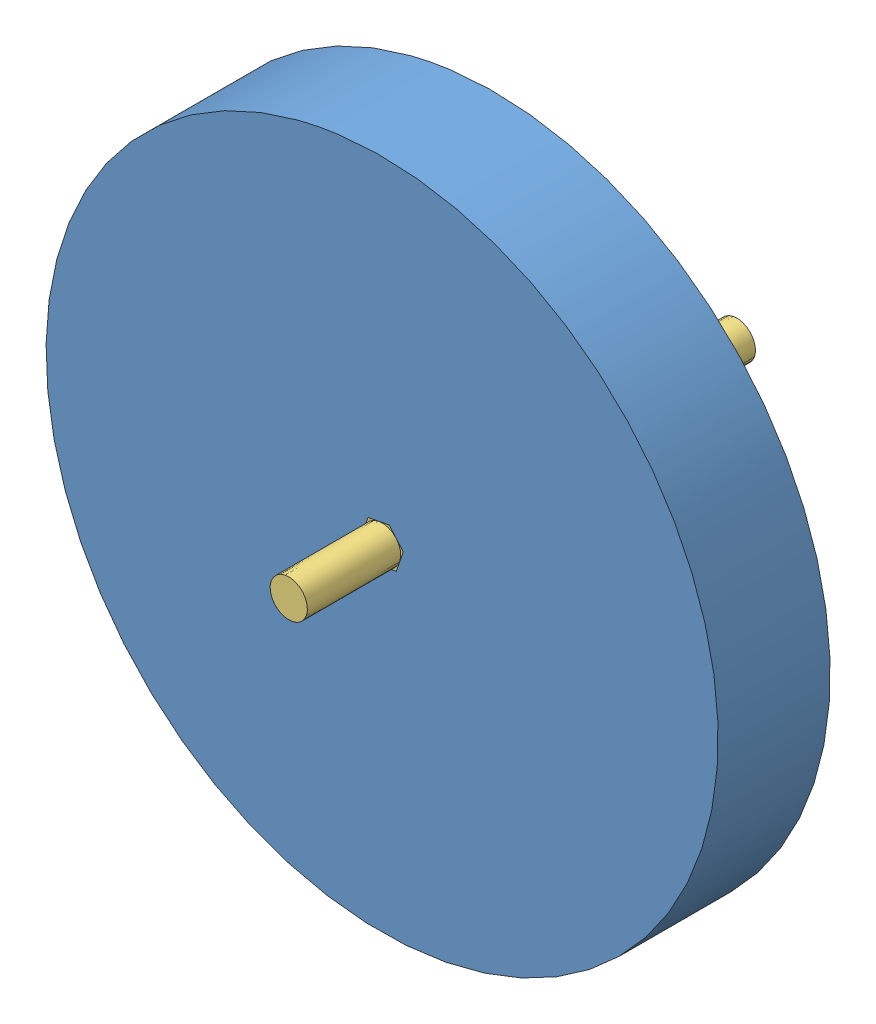
SolidWorks assembly Drivetrain wheel axle and belt gear free, configuration Default. Lengths in mm.
Overall size (133.9 133.9 76.2).
3 component instances, 3 part files, 9 mates.
Components (placement in the parent):
- Wheel-1: Wheel [Default] at (0 57.15 19.05) x (-0.189612 0.981859 0) z (0 0 -1) size (114.3 114.3 19.05)
- belt gear-2: belt gear [Default] at (0 57.15 -12.7) x (-0.945121 0.326721 0) z (0 0 1) size (39.94 39.94 6.35)
- wheel axle free-1: wheel axle free [Default] at (0 57.15 34.925) x (-0.755509 -0.655138 0) z (0 0 -1) size (6.35 7.33 76.2)
Mates (geometry in assembly coordinates):
- Coincident3: coincident: circle of Wheel-1; point of assembly
- Tangent1: tangent: cylinder of Wheel-1 through (0 57.15 0) axis (0 0 1) radius 57.15; plane of assembly through (0 0 0) normal (0 1 0)
- Parallel1: parallel: plane of Wheel-1 through (0 57.15 19.05) normal (0 0 1); plane of assembly through (0 0 0) normal (0 0 1)
- Distance1: distance = 6.35 mm: plane of belt gear-2 through (0 57.15 -6.35) normal (0 0 1); plane of Wheel-1 through (0 57.15 0) normal (0 0 -1)
- Coincident4: coincident: plane of Wheel-1 through (0 57.15 19.05) normal (0 0 1); plane of wheel axle free-1 through (0 57.15 19.05) normal (0 0 1)
- Coincident5: coincident: plane of Wheel-1 through (1.1978 60.615 0) normal (0.189612 -0.981859 0); plane of wheel axle free-1 through (-2.4019 59.9198 -41.275) normal (-0.189612 0.981859 0)
- Coincident6: coincident: plane of Wheel-1 through (3.5997 57.8451 0) normal (-0.755509 -0.655138 0); plane of wheel axle free-1 through (1.1978 60.615 -41.275) normal (0.755509 0.655138 0)
- Coincident7: coincident: plane of belt gear-2 through (3.5997 57.8451 -6.35) normal (-0.755509 -0.655138 0); plane of wheel axle free-1 through (1.1978 60.615 -41.275) normal (0.755509 0.655138 0)
- Coincident8: coincident: plane of belt gear-2 through (2.4019 54.3802 -6.35) normal (-0.945121 0.326721 0); plane of wheel axle free-1 through (3.5997 57.8451 -41.275) normal (0.945121 -0.326721 0)
